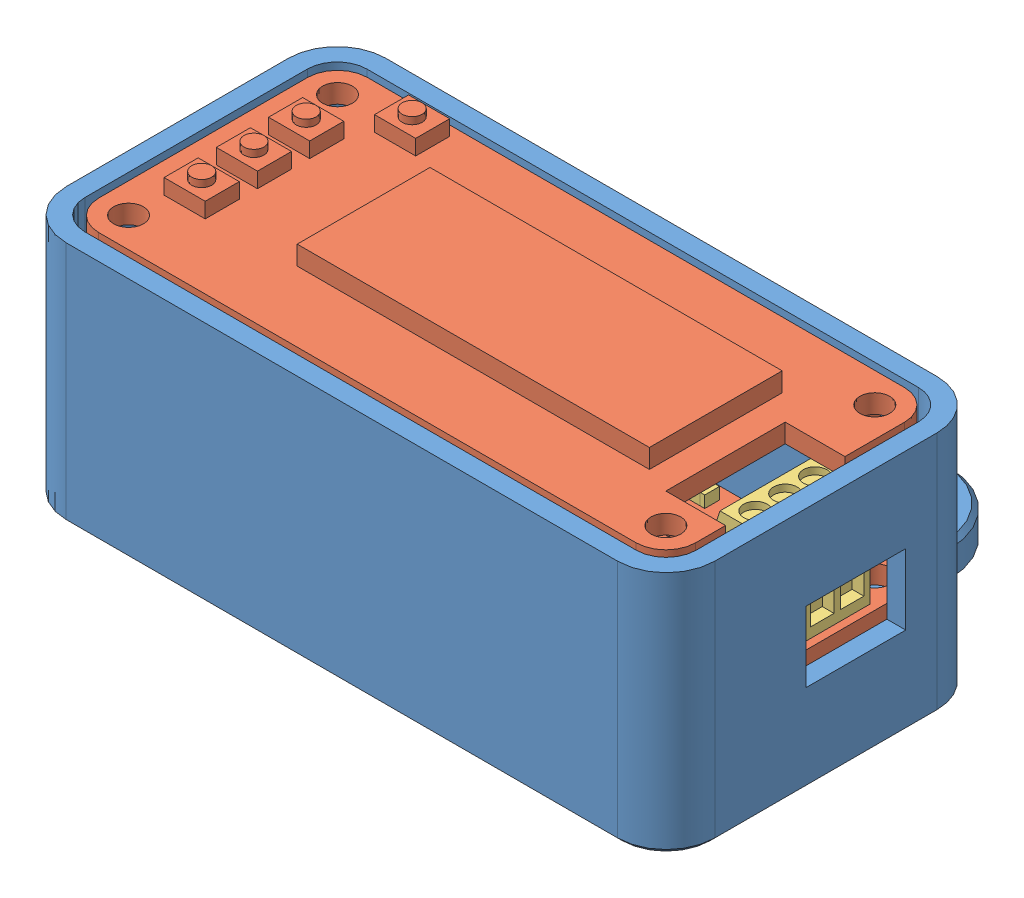
SolidWorks assembly tachometer, configuration Default. Lengths in mm.
Overall size (55.2 22.67 39.2).
46 component instances, 23 part files, 23 mates.
Components (placement in the parent):
- feather_casing-1: feather_casing [Default] at origin size (55.2 20.8 39.2)
- 3857 Adafruit Feather M4 Express-1: 3857 Adafruit Feather M4 Express [Default] at (-25.4 3.6 11.43) x (1 0 0) z (0 1 0) size (50.85 22.86 6.37)
  - 3857 Adafruit Feather M4 Express(2)^3857 Adafruit Feather M4 Express-1: 3857 Adafruit Feather M4 Express(2)^3857 Adafruit Feather M4 Express [Default] at origin size (50.85 22.86 6.37) (virtual)
    - PCB Component^3857 Adafruit Feather M4 Express(2)_3857 Adafruit Feather M4 Express-1: PCB Component^3857 Adafruit Feather M4 Express(2)_3857 Adafruit Feather M4 Express [Default] at origin size (50.85 22.86 6.37) (virtual)
      - Board^PCB Component_3857 Adafruit Feather M4 Express(2)_3857 Adafruit Feather M4 Express-1: Board^PCB Component_3857 Adafruit Feather M4 Express(2)_3857 Adafruit Feather M4 Express [Default] at origin size (50.8 22.86 1.57) (virtual)
      - 10uF^PCB Component_3857 Adafruit Feather M4 Express(2)_3857 Adafruit Feather M4 Express-1: 10uF^PCB Component_3857 Adafruit Feather M4 Express(2)_3857 Adafruit Feather M4 Express [Default] at (12.042 9.838 1.57) x (0 -1 0) z (0 0 1) size (2 1.25 1) (virtual)
      - 10uF^PCB Component_3857 Adafruit Feather M4 Express(2)_3857 Adafruit Feather M4 Express-2: 10uF^PCB Component_3857 Adafruit Feather M4 Express(2)_3857 Adafruit Feather M4 Express [Default] at (14.728 13.858 1.57) size (2 1.25 1) (virtual)
      - 10uF^PCB Component_3857 Adafruit Feather M4 Express(2)_3857 Adafruit Feather M4 Express-3: 10uF^PCB Component_3857 Adafruit Feather M4 Express(2)_3857 Adafruit Feather M4 Express [Default] at (15.748 17.272 1.57) x (0 -1 0) z (0 0 1) size (2 1.25 1) (virtual)
      - 10uF^PCB Component_3857 Adafruit Feather M4 Express(2)_3857 Adafruit Feather M4 Express-4: 10uF^PCB Component_3857 Adafruit Feather M4 Express(2)_3857 Adafruit Feather M4 Express [Default] at (35.065 18.669 1.57) size (2 1.25 1) (virtual)
      - 10uF^PCB Component_3857 Adafruit Feather M4 Express(2)_3857 Adafruit Feather M4 Express-5: 10uF^PCB Component_3857 Adafruit Feather M4 Express(2)_3857 Adafruit Feather M4 Express [Default] at (18.796 11.303 1.57) x (0 -1 0) z (0 0 1) size (2 1.25 1) (virtual)
      - 1uF^PCB Component_3857 Adafruit Feather M4 Express(2)_3857 Adafruit Feather M4 Express-1: 1uF^PCB Component_3857 Adafruit Feather M4 Express(2)_3857 Adafruit Feather M4 Express [Default] at (24.909 17.78 1.57) x (0 1 0) z (0 0 1) size (1.6 0.9 0.8) (virtual)
      - 1uF^PCB Component_3857 Adafruit Feather M4 Express(2)_3857 Adafruit Feather M4 Express-2: 1uF^PCB Component_3857 Adafruit Feather M4 Express(2)_3857 Adafruit Feather M4 Express [Default] at (11.989 4.218 1.57) size (1.6 0.9 0.8) (virtual)
      - 1uF^PCB Component_3857 Adafruit Feather M4 Express(2)_3857 Adafruit Feather M4 Express-3: 1uF^PCB Component_3857 Adafruit Feather M4 Express(2)_3857 Adafruit Feather M4 Express [Default] at (5.715 20.955 1.57) x (0 -1 0) z (0 0 1) size (1.6 0.9 0.8) (virtual)
      - 1uF^PCB Component_3857 Adafruit Feather M4 Express(2)_3857 Adafruit Feather M4 Express-4: 1uF^PCB Component_3857 Adafruit Feather M4 Express(2)_3857 Adafruit Feather M4 Express [Default] at (5.829 4.254 1.57) size (1.6 0.9 0.8) (virtual)
      - 1uF^PCB Component_3857 Adafruit Feather M4 Express(2)_3857 Adafruit Feather M4 Express-5: 1uF^PCB Component_3857 Adafruit Feather M4 Express(2)_3857 Adafruit Feather M4 Express [Default] at (18.415 17.97 1.57) size (1.6 0.9 0.8) (virtual)
      - 1uF^PCB Component_3857 Adafruit Feather M4 Express(2)_3857 Adafruit Feather M4 Express-6: 1uF^PCB Component_3857 Adafruit Feather M4 Express(2)_3857 Adafruit Feather M4 Express [Default] at (19.202 5.067 1.57) x (0 1 0) z (0 0 1) size (1.6 0.9 0.8) (virtual)
      - 1uF^PCB Component_3857 Adafruit Feather M4 Express(2)_3857 Adafruit Feather M4 Express-7: 1uF^PCB Component_3857 Adafruit Feather M4 Express(2)_3857 Adafruit Feather M4 Express [Default] at (21.526 6.35 1.57) x (-1 0 0) z (0 0 1) size (1.6 0.9 0.8) (virtual)
      - 1uF^PCB Component_3857 Adafruit Feather M4 Express(2)_3857 Adafruit Feather M4 Express-8: 1uF^PCB Component_3857 Adafruit Feather M4 Express(2)_3857 Adafruit Feather M4 Express [Default] at (36.119 4.648 1.57) x (-1 0 0) z (0 0 1) size (1.6 0.9 0.8) (virtual)
      - 1uF^PCB Component_3857 Adafruit Feather M4 Express(2)_3857 Adafruit Feather M4 Express-9: 1uF^PCB Component_3857 Adafruit Feather M4 Express(2)_3857 Adafruit Feather M4 Express [Default] at (19.126 8.065 1.57) x (0 1 0) z (0 0 1) size (1.6 0.9 0.8) (virtual)
      - 1uF^PCB Component_3857 Adafruit Feather M4 Express(2)_3857 Adafruit Feather M4 Express-10: 1uF^PCB Component_3857 Adafruit Feather M4 Express(2)_3857 Adafruit Feather M4 Express [Default] at (29.662 5.263 1.57) x (-1 0 0) z (0 0 1) size (1.6 0.9 0.8) (virtual)
      - 1uF^PCB Component_3857 Adafruit Feather M4 Express(2)_3857 Adafruit Feather M4 Express-11: 1uF^PCB Component_3857 Adafruit Feather M4 Express(2)_3857 Adafruit Feather M4 Express [Default] at (8.89 4.254 1.57) x (-1 0 0) z (0 0 1) size (1.6 0.9 0.8) (virtual)
      - 1uF^PCB Component_3857 Adafruit Feather M4 Express(2)_3857 Adafruit Feather M4 Express-12: 1uF^PCB Component_3857 Adafruit Feather M4 Express(2)_3857 Adafruit Feather M4 Express [Default] at (17.145 10.922 1.57) x (0 1 0) z (0 0 1) size (1.6 0.9 0.8) (virtual)
      - 1uF^PCB Component_3857 Adafruit Feather M4 Express(2)_3857 Adafruit Feather M4 Express-13: 1uF^PCB Component_3857 Adafruit Feather M4 Express(2)_3857 Adafruit Feather M4 Express [Default] at (13.856 6.502 1.57) x (0 -1 0) z (0 0 1) size (1.6 0.9 0.8) (virtual)
      - 1uF^PCB Component_3857 Adafruit Feather M4 Express(2)_3857 Adafruit Feather M4 Express-14: 1uF^PCB Component_3857 Adafruit Feather M4 Express(2)_3857 Adafruit Feather M4 Express [Default] at (21.4 8.065 1.57) size (1.6 0.9 0.8) (virtual)
      - 1uF^PCB Component_3857 Adafruit Feather M4 Express(2)_3857 Adafruit Feather M4 Express-15: 1uF^PCB Component_3857 Adafruit Feather M4 Express(2)_3857 Adafruit Feather M4 Express [Default] at (22.225 14.414 1.57) x (-1 0 0) z (0 0 1) size (1.6 0.9 0.8) (virtual)
      - ORANGE^PCB Component_3857 Adafruit Feather M4 Express(2)_3857 Adafruit Feather M4 Express-1: ORANGE^PCB Component_3857 Adafruit Feather M4 Express(2)_3857 Adafruit Feather M4 Express [Default] at (2.645 17.359 1.57) x (0 1 0) z (0 0 1) size (1.25 2.02 1.1) (virtual)
      - ORANGE^PCB Component_3857 Adafruit Feather M4 Express(2)_3857 Adafruit Feather M4 Express-2: ORANGE^PCB Component_3857 Adafruit Feather M4 Express(2)_3857 Adafruit Feather M4 Express [Default] at (2.413 5.588 1.57) x (0 -1 0) z (0 0 1) size (1.25 2.02 1.1) (virtual)
      - KMR2^PCB Component_3857 Adafruit Feather M4 Express(2)_3857 Adafruit Feather M4 Express-1: KMR2^PCB Component_3857 Adafruit Feather M4 Express(2)_3857 Adafruit Feather M4 Express [Default] at (9.398 6.54 1.57) x (-1 0 0) z (0 0 1) size (4.6 2.8 1.94) (virtual)
      - microUSB^PCB Component_3857 Adafruit Feather M4 Express(2)_3857 Adafruit Feather M4 Express-1: microUSB^PCB Component_3857 Adafruit Feather M4 Express(2)_3857 Adafruit Feather M4 Express [Default] at (4.445 11.43 1.57) x (0 -1 0) z (0 0 1) size (8.8 5.6 3) (virtual)
      - MCP73831T-2ACI_OT^PCB Component_3857 Adafruit Feather M4 Express(2)_3857 Adafruit Feather M4 Express-1: MCP73831T-2ACI_OT^PCB Component_3857 Adafruit Feather M4 Express(2)_3857 Adafruit Feather M4 Express [Default] at (14.732 10.922 1.57) size (3 3 1.4) (virtual)
      - MCP73831T-2ACI_OT^PCB Component_3857 Adafruit Feather M4 Express(2)_3857 Adafruit Feather M4 Express-2: MCP73831T-2ACI_OT^PCB Component_3857 Adafruit Feather M4 Express(2)_3857 Adafruit Feather M4 Express [Default] at (18.352 15.113 1.57) size (3 3 1.4) (virtual)
      - JSTPH^PCB Component_3857 Adafruit Feather M4 Express(2)_3857 Adafruit Feather M4 Express-1: JSTPH^PCB Component_3857 Adafruit Feather M4 Express(2)_3857 Adafruit Feather M4 Express [Default] at (10.795 19.304 1.57) size (7.9 8.6 4.8) (virtual)
      - 32.768^PCB Component_3857 Adafruit Feather M4 Express(2)_3857 Adafruit Feather M4 Express-1: 32.768^PCB Component_3857 Adafruit Feather M4 Express(2)_3857 Adafruit Feather M4 Express [Default] at (21.806 4.496 1.57) x (-1 0 0) z (0 0 1) size (3.5 1.5 0.8) (virtual)
      - WS2812B3535^PCB Component_3857 Adafruit Feather M4 Express(2)_3857 Adafruit Feather M4 Express-1: WS2812B3535^PCB Component_3857 Adafruit Feather M4 Express(2)_3857 Adafruit Feather M4 Express [Default] at (16.485 6.109 1.57) x (0 -1 0) z (0 0 1) size (3.5 3.5 1.2) (virtual)
      - 2MB Flash^PCB Component_3857 Adafruit Feather M4 Express(2)_3857 Adafruit Feather M4 Express-1: 2MB Flash^PCB Component_3857 Adafruit Feather M4 Express(2)_3857 Adafruit Feather M4 Express [Default] at (36.512 8.433 1.57) x (0 1 0) z (0 0 1) size (3 2 0.8) (virtual)
      - MBR120^PCB Component_3857 Adafruit Feather M4 Express(2)_3857 Adafruit Feather M4 Express-1: MBR120^PCB Component_3857 Adafruit Feather M4 Express(2)_3857 Adafruit Feather M4 Express [Default] at (10.35 12.319 1.57) x (-1 0 0) z (0 0 1) size (3.6 1.4 1.35) (virtual)
      - DMG341^PCB Component_3857 Adafruit Feather M4 Express(2)_3857 Adafruit Feather M4 Express-1: DMG341^PCB Component_3857 Adafruit Feather M4 Express(2)_3857 Adafruit Feather M4 Express [Default] at (9.398 9.842 1.57) size (3.04 2.64 1.12) (virtual)
      - 100K^PCB Component_3857 Adafruit Feather M4 Express(2)_3857 Adafruit Feather M4 Express-1: 100K^PCB Component_3857 Adafruit Feather M4 Express(2)_3857 Adafruit Feather M4 Express [Default] at (22.67 17.208 1.57) x (0 1 0) z (0 0 1) size (3.05 1.6 0.5) (virtual)
      - ATSAMD51J^PCB Component_3857 Adafruit Feather M4 Express(2)_3857 Adafruit Feather M4 Express-1: ATSAMD51J^PCB Component_3857 Adafruit Feather M4 Express(2)_3857 Adafruit Feather M4 Express [Default] at (30.162 11.049 1.57) x (0 1 0) z (0 0 1) size (9 9 0.8) (virtual)
      - 10uH^PCB Component_3857 Adafruit Feather M4 Express(2)_3857 Adafruit Feather M4 Express-1: 10uH^PCB Component_3857 Adafruit Feather M4 Express(2)_3857 Adafruit Feather M4 Express [Default] at (21.082 11.811 1.57) x (0 -1 0) z (0 0 1) size (2.7 2 2) (virtual)
- header_f16-1: header_f16 [Default] at (-20.445 5.17 10.16) size (40.89 11.5 2.5)
- header_f12-1: header_f12 [Default] at (-10.285 5.17 -10.16) size (30.73 11.5 2.5)
- 2900 Feather OLED Wing-1: 2900 Feather OLED Wing [Default] at (-25.4 17.77 11.43) x (1 0 0) z (0 1 0) size (50.8 22.86 6)
- screw_terminal_3x_2.54pitch_Multicomp_MP008514-1: screw_terminal_3x_2.54pitch_Multicomp_MP008514 [Default] at (18.44 5.17 1.51) size (6.3 12.4 8.1)
- ISO - 4032 - M2.5 - D - N-1: ISO - 4032 - M2.5 - D - N [ISO - 4032 - M2.5 - D - N] at (-22.86 -2.6 -8.89) x (0.866025 0 -0.5) z (0 -1 0) size (5 5.77 2)
- ISO 4762 M2.5 x 8 - 8N-1: ISO 4762 M2.5 x 8 - 8N [ISO 4762 M2.5 x 8 - 8N] at (-22.86 7.67 -8.89) x (0 -1 0) z (0 0 1) size (10.5 4.5 4.5)
Mates (geometry in assembly coordinates):
- Concentric1: concentric anti-aligned: cylinder of 3857 Adafruit Feather M4 Express-1/3857 Adafruit Feather M4 Express(2)^3857 Adafruit Feather M4 Express-1/PCB Component^3857 Adafruit Feather M4 Express(2)_3857 Adafruit Feather M4 Express-1/Board^PCB Component_3857 Adafruit Feather M4 Express(2)_3857 Adafruit Feather M4 Express-1 through (-19.05 3.6 10.16) axis (0 1 0) radius 0.5; line of header_f16-1 through (-19.05 5.17 10.16) axis (0 -1 0)
- Concentric2: concentric anti-aligned: cylinder of 3857 Adafruit Feather M4 Express-1/3857 Adafruit Feather M4 Express(2)^3857 Adafruit Feather M4 Express-1/PCB Component^3857 Adafruit Feather M4 Express(2)_3857 Adafruit Feather M4 Express-1/Board^PCB Component_3857 Adafruit Feather M4 Express(2)_3857 Adafruit Feather M4 Express-1 through (19.05 3.6 10.16) axis (0 1 0) radius 0.5; line of header_f16-1 through (19.05 5.17 10.16) axis (0 -1 0)
- Coincident5: coincident anti-aligned: plane of 3857 Adafruit Feather M4 Express-1/3857 Adafruit Feather M4 Express(2)^3857 Adafruit Feather M4 Express-1/PCB Component^3857 Adafruit Feather M4 Express(2)_3857 Adafruit Feather M4 Express-1/Board^PCB Component_3857 Adafruit Feather M4 Express(2)_3857 Adafruit Feather M4 Express-1 through (0 5.17 0) normal (0 1 0); plane of header_f16-1 through (-20.445 5.17 11.41) normal (0 -1 0)
- Concentric3: concentric anti-aligned: cylinder of 3857 Adafruit Feather M4 Express-1/3857 Adafruit Feather M4 Express(2)^3857 Adafruit Feather M4 Express-1/PCB Component^3857 Adafruit Feather M4 Express(2)_3857 Adafruit Feather M4 Express-1/Board^PCB Component_3857 Adafruit Feather M4 Express(2)_3857 Adafruit Feather M4 Express-1 through (-8.89 3.6 -10.16) axis (0 1 0) radius 0.5; line of header_f12-1 through (-8.89 5.17 -10.16) axis (0 -1 0)
- Concentric4: concentric anti-aligned: cylinder of 3857 Adafruit Feather M4 Express-1/3857 Adafruit Feather M4 Express(2)^3857 Adafruit Feather M4 Express-1/PCB Component^3857 Adafruit Feather M4 Express(2)_3857 Adafruit Feather M4 Express-1/Board^PCB Component_3857 Adafruit Feather M4 Express(2)_3857 Adafruit Feather M4 Express-1 through (19.05 3.6 -10.16) axis (0 1 0) radius 0.5; line of header_f12-1 through (19.05 5.17 -10.16) axis (0 -1 0)
- Coincident6: coincident anti-aligned: plane of 3857 Adafruit Feather M4 Express-1/3857 Adafruit Feather M4 Express(2)^3857 Adafruit Feather M4 Express-1/PCB Component^3857 Adafruit Feather M4 Express(2)_3857 Adafruit Feather M4 Express-1/Board^PCB Component_3857 Adafruit Feather M4 Express(2)_3857 Adafruit Feather M4 Express-1 through (0 5.17 0) normal (0 1 0); plane of header_f12-1 through (-10.285 5.17 -8.91) normal (0 -1 0)
- Coincident7: coincident anti-aligned: plane of header_f16-1 through (-20.445 13.67 11.41) normal (0 1 0); plane of 2900 Feather OLED Wing-1 through (0.8 13.67 10.18) normal (0 -1 0)
- Concentric5: concentric anti-aligned: cylinder of 3857 Adafruit Feather M4 Express-1/3857 Adafruit Feather M4 Express(2)^3857 Adafruit Feather M4 Express-1/PCB Component^3857 Adafruit Feather M4 Express(2)_3857 Adafruit Feather M4 Express-1/Board^PCB Component_3857 Adafruit Feather M4 Express(2)_3857 Adafruit Feather M4 Express-1 through (-22.86 3.6 8.89) axis (0 1 0) radius 1.25; cylinder of 2900 Feather OLED Wing-1 through (-22.86 17.77 8.89) axis (0 -1 0) radius 1.27
- Concentric6: concentric anti-aligned: cylinder of 3857 Adafruit Feather M4 Express-1/3857 Adafruit Feather M4 Express(2)^3857 Adafruit Feather M4 Express-1/PCB Component^3857 Adafruit Feather M4 Express(2)_3857 Adafruit Feather M4 Express-1/Board^PCB Component_3857 Adafruit Feather M4 Express(2)_3857 Adafruit Feather M4 Express-1 through (-22.86 3.6 -8.89) axis (0 1 0) radius 1.25; cylinder of 2900 Feather OLED Wing-1 through (-22.86 17.77 -8.89) axis (0 -1 0) radius 1.27
- Coincident8: coincident anti-aligned: plane of 3857 Adafruit Feather M4 Express-1/3857 Adafruit Feather M4 Express(2)^3857 Adafruit Feather M4 Express-1/PCB Component^3857 Adafruit Feather M4 Express(2)_3857 Adafruit Feather M4 Express-1/Board^PCB Component_3857 Adafruit Feather M4 Express(2)_3857 Adafruit Feather M4 Express-1 through (0 5.17 0) normal (0 1 0); plane of screw_terminal_3x_2.54pitch_Multicomp_MP008514-1 through (24.74 5.17 -6.59) normal (0 -1 0)
- Concentric7: concentric anti-aligned: cylinder of 3857 Adafruit Feather M4 Express-1/3857 Adafruit Feather M4 Express(2)^3857 Adafruit Feather M4 Express-1/PCB Component^3857 Adafruit Feather M4 Express(2)_3857 Adafruit Feather M4 Express-1/Board^PCB Component_3857 Adafruit Feather M4 Express(2)_3857 Adafruit Feather M4 Express-1 through (21.59 3.6 0) axis (0 1 0) radius 0.55; line of screw_terminal_3x_2.54pitch_Multicomp_MP008514-1 through (5.1519 21.59 5.17) axis (0 0 -1)
- Parallel1: parallel aligned: plane of 3857 Adafruit Feather M4 Express-1 through (-25.4 3.6 11.43) normal (1 0 0); plane of screw_terminal_3x_2.54pitch_Multicomp_MP008514-1 through (18.44 5.17 1.51) normal (1 0 0)
- Coincident10: coincident aligned: plane of feather_casing-1 through (0 0 0) normal (0 0 1)
- Coincident11: coincident aligned: plane of feather_casing-1 through (0 0 0) normal (0 1 0)
- Coincident12: coincident aligned: plane of feather_casing-1 through (0 0 0) normal (1 0 0)
- Coincident9: coincident anti-aligned: plane of 3857 Adafruit Feather M4 Express-1/3857 Adafruit Feather M4 Express(2)^3857 Adafruit Feather M4 Express-1/PCB Component^3857 Adafruit Feather M4 Express(2)_3857 Adafruit Feather M4 Express-1/Board^PCB Component_3857 Adafruit Feather M4 Express(2)_3857 Adafruit Feather M4 Express-1 through (0 3.6 0) normal (0 -1 0); plane of feather_casing-1 through (-23 3.6 -9) normal (0 1 0)
- Coincident13: coincident anti-aligned: plane of ISO - 4032 - M2.5 - D - N-1 through (-27.1901 -0.6 -6.39) normal (0 1 0); plane of feather_casing-1 through (0 -0.6 0) normal (0 -1 0)
- Concentric8: concentric anti-aligned: cylinder of feather_casing-1 through (-22.86 -3 -8.89) axis (0 1 0) radius 1.3; cylinder of ISO - 4032 - M2.5 - D - N-1 through (-22.86 -0.6 -8.89) axis (0 -1 0) radius 1.025
- Parallel2: parallel anti-aligned: plane of ISO - 4032 - M2.5 - D - N-1 through (-24.3034 -0.6 -11.39) normal (0 0 -1); plane of feather_casing-1 through (-24.3611 -0.6 -11.49) normal (0 0 1)
- Concentric9: concentric aligned: cylinder of feather_casing-1 through (-22.86 -3 -8.89) axis (0 1 0) radius 1.3; cylinder of 3857 Adafruit Feather M4 Express-1/3857 Adafruit Feather M4 Express(2)^3857 Adafruit Feather M4 Express-1/PCB Component^3857 Adafruit Feather M4 Express(2)_3857 Adafruit Feather M4 Express-1/Board^PCB Component_3857 Adafruit Feather M4 Express(2)_3857 Adafruit Feather M4 Express-1 through (-22.86 3.6 -8.89) axis (0 1 0) radius 1.25
- Parallel3: parallel anti-aligned: plane of 3857 Adafruit Feather M4 Express-1 through (-25.4 3.6 11.43) normal (0 0 -1)
- Concentric101: concentric aligned: cylinder of 3857 Adafruit Feather M4 Express-1/3857 Adafruit Feather M4 Express(2)^3857 Adafruit Feather M4 Express-1/PCB Component^3857 Adafruit Feather M4 Express(2)_3857 Adafruit Feather M4 Express-1/Board^PCB Component_3857 Adafruit Feather M4 Express(2)_3857 Adafruit Feather M4 Express-1 through (-22.86 3.6 -8.89) axis (0 1 0) radius 1.25; cylinder of ISO 4762 M2.5 x 8 - 8N-1 through (-22.86 39.42 -8.89) axis (0 1 0) radius 2.25
- Coincident161: coincident anti-aligned: plane of 3857 Adafruit Feather M4 Express-1/3857 Adafruit Feather M4 Express(2)^3857 Adafruit Feather M4 Express-1/PCB Component^3857 Adafruit Feather M4 Express(2)_3857 Adafruit Feather M4 Express-1/Board^PCB Component_3857 Adafruit Feather M4 Express(2)_3857 Adafruit Feather M4 Express-1 through (0 5.17 0) normal (0 1 0); plane of ISO 4762 M2.5 x 8 - 8N-1 through (-20.61 5.17 -8.89) normal (0 -1 0)
